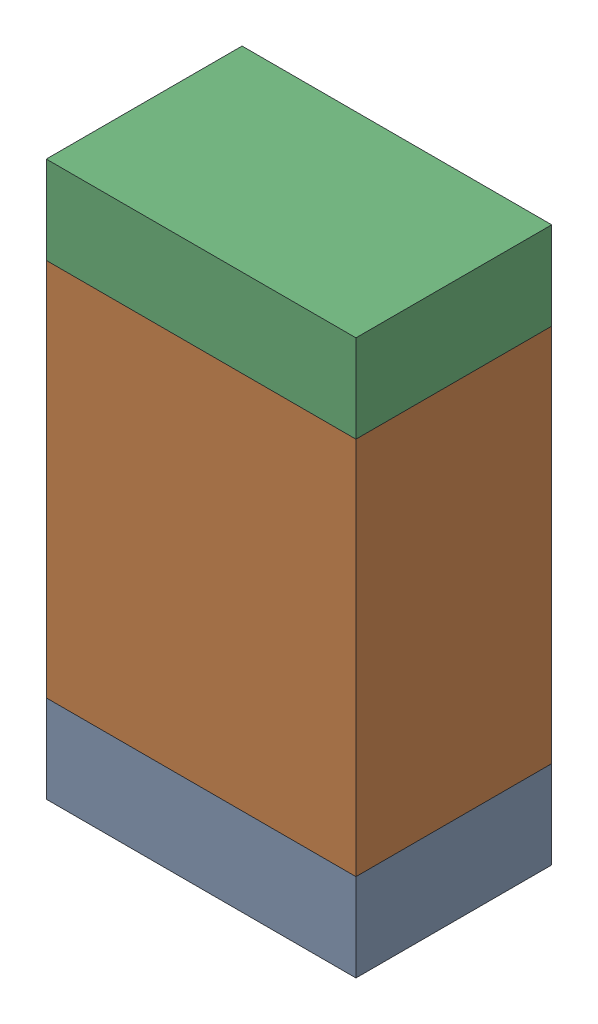
SolidWorks assembly R1-1, configuration Default. Lengths in mm.
Overall size (0.95 1.7 0.6).
6 component instances, 2 part files, 0 mates.
Components (placement in the parent):
- 959206216-1-1: 959206216-1 [Default] at (142.6211 77.6287 0) size (0.95 0.27 0.6)
  - Extruded-31-1: Extruded-31 [Default] at origin size (0.95 0.27 0.6)
- 959206352-1-1: 959206352-1 [Default] at (142.6211 78.3437 0) size (0.95 1.16 0.6)
  - Extruded-32-1: Extruded-32 [Default] at origin size (0.95 1.16 0.6)
- 959206216-1-2: 959206216-1 [Default] at (142.6211 79.0587 0) size (0.95 0.27 0.6)
  - Extruded-31-1: Extruded-31 [Default] at origin size (0.95 0.27 0.6)
